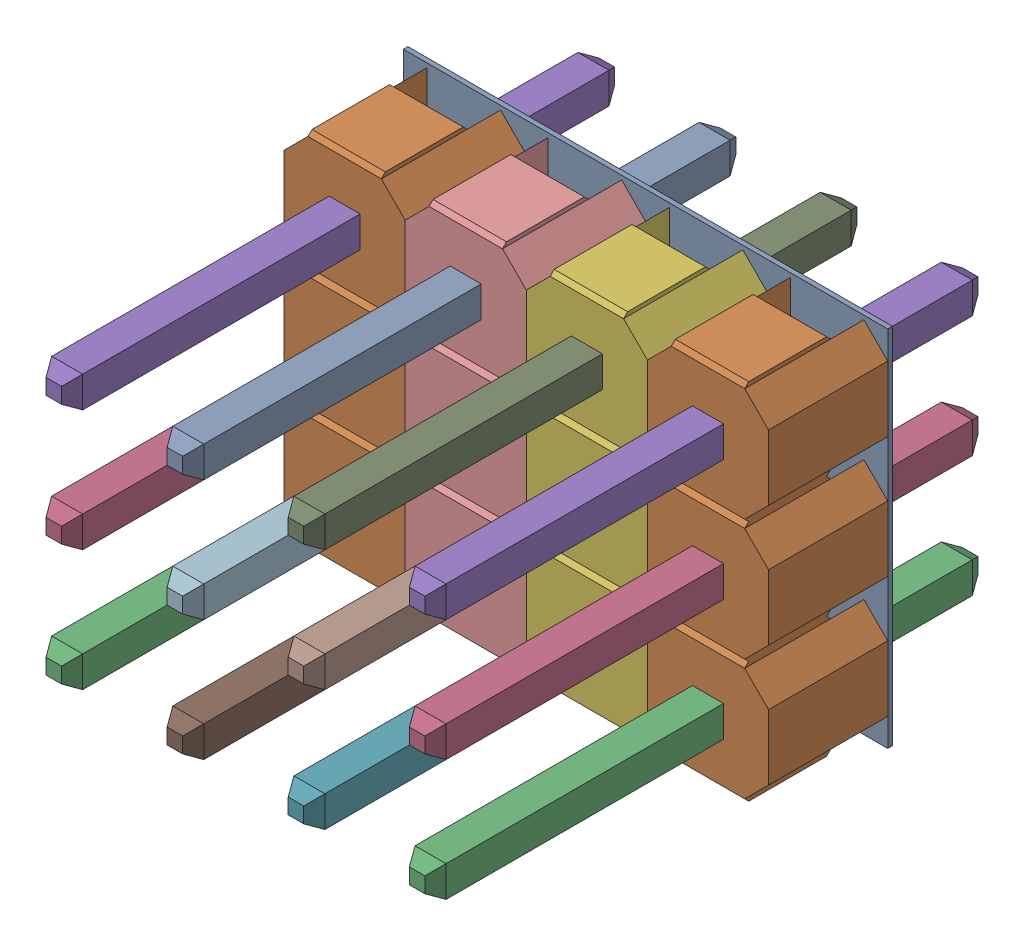
SolidWorks assembly PCB, configuration 默认. Lengths in mm.
Overall size (10.16 7.62 11.6).
10 component instances, 2 part files, 0 mates.
Components (placement in the parent):
- Board-1: Board [默认] at origin size (10.16 7.62 0.1)
  - Open CASCADE STEP translator 6.8 6.1.1-1: Open CASCADE STEP translator 6.8 6.1.1 [默认] at (0 0 -0.0965) size (10.16 7.62 0.1)
- Z_RST3-1: Z_RST3 [默认] at origin size (2.54 7.62 11.6)
  - DS1021-1x3SF11-1: DS1021-1x3SF11 [默认] at (8.8901 1.2699 0) x (0 1 0) z (0 0 1) size (7.62 2.54 11.6)
- Z_RST2-1: Z_RST2 [默认] at origin size (2.54 7.62 11.6)
  - DS1021-1x3SF11-1: DS1021-1x3SF11 [默认] at (6.3501 1.2699 0) x (0 1 0) z (0 0 1) size (7.62 2.54 11.6)
- Z_RST1-1: Z_RST1 [默认] at origin size (2.54 7.62 11.6)
  - DS1021-1x3SF11-1: DS1021-1x3SF11 [默认] at (3.8101 1.2699 0) x (0 1 0) z (0 0 1) size (7.62 2.54 11.6)
- Z_RST-1: Z_RST [默认] at origin size (2.54 7.62 11.6)
  - DS1021-1x3SF11-1: DS1021-1x3SF11 [默认] at (1.2701 1.2699 0) x (0 1 0) z (0 0 1) size (7.62 2.54 11.6)
